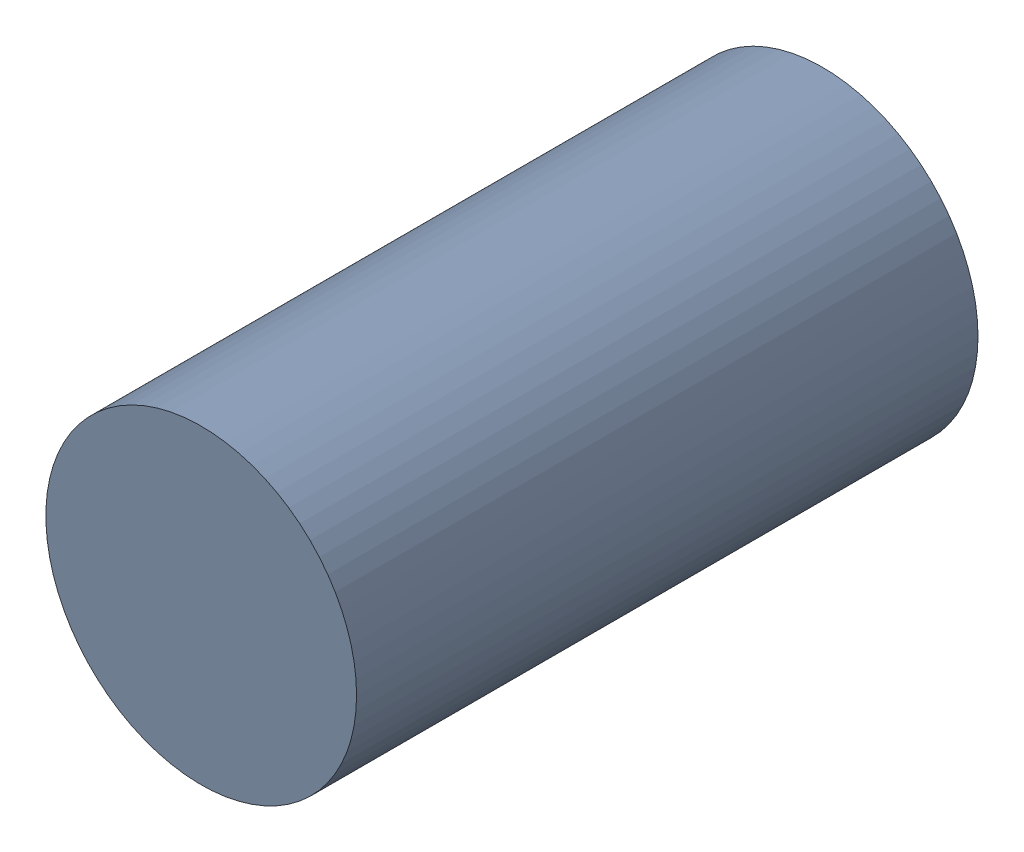
SolidWorks assembly MH9_3.step, configuration Default. Lengths in mm.
Overall size (1 1 2).
2 component instances, 1 part files, 0 mates.
Components (placement in the parent):
- 9228463120_2.step-2: 9228463120_2.step [Default] at (42.498 92.1677 -1.5) size (1 1 2)
  - Cylinder_4.step-7: Cylinder_4.step [Default] at origin size (1 1 2)
